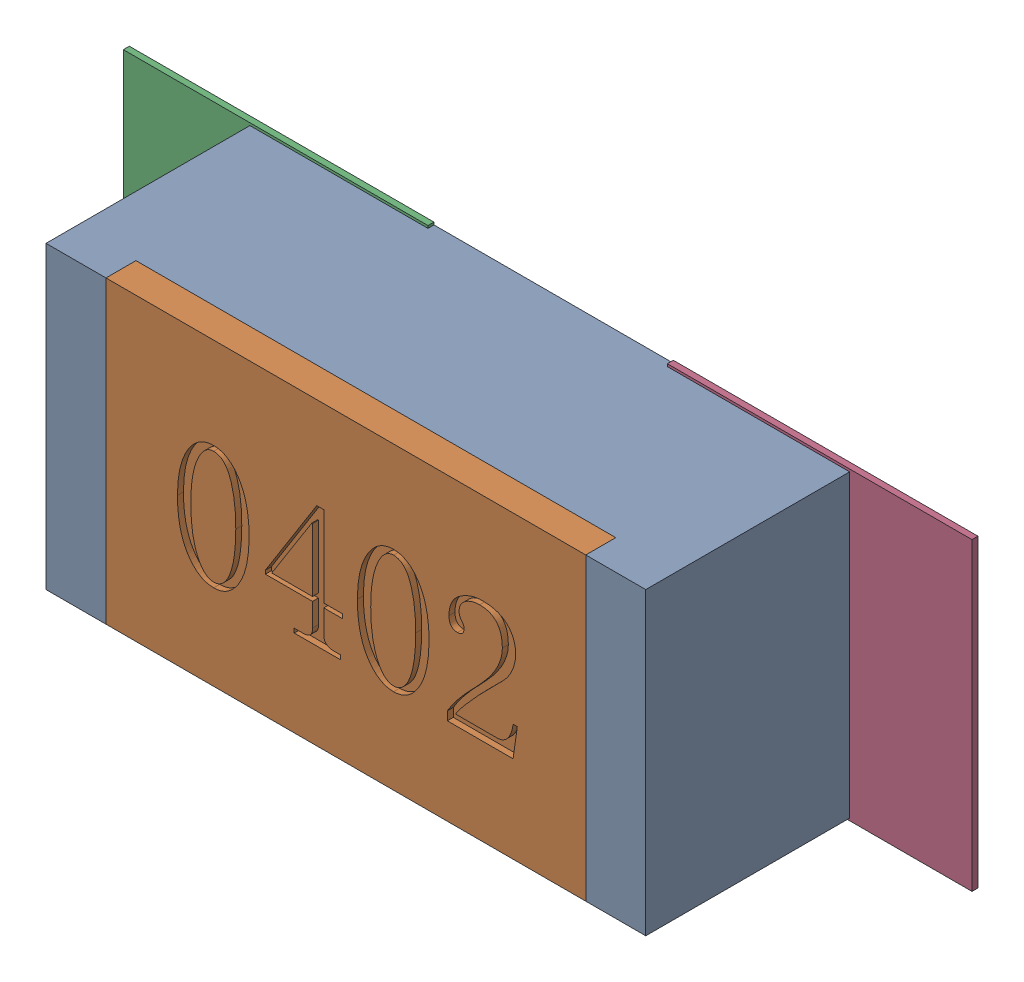
SolidWorks assembly R142, configuration Défaut. Lengths in mm.
Overall size (1.42 0.51 0.35).
5 component instances, 2 part files, 0 mates.
Components (placement in the parent):
- R0402-1: R0402 [Défaut] at (12.2936 -26.1663 0) x (1 0 0) z (0 0 1) size (1 0.5 0.35)
- 6504207776-1: 6504207776 [Défaut] at (11.8365 -26.1662 0) size (0.51 0.51 0.01)
  - Extruded-1: Extruded [Défaut] at origin size (0.51 0.51 0.01)
- 6504207776-2: 6504207776 [Défaut] at (12.7436 -26.1662 0) size (0.51 0.51 0.01)
  - Extruded-1: Extruded [Défaut] at origin size (0.51 0.51 0.01)
